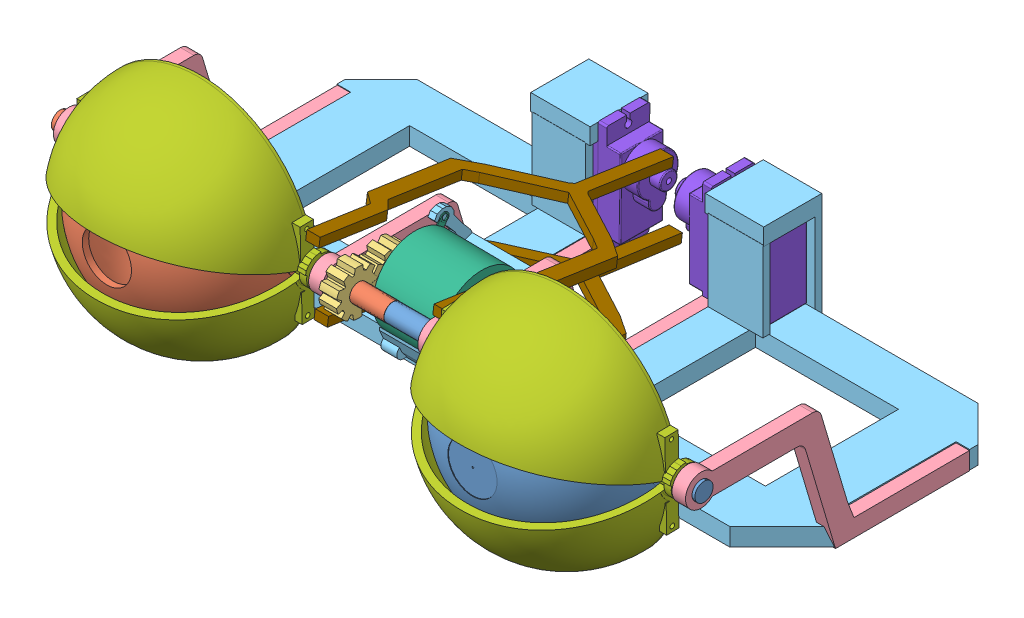
SolidWorks assembly EyeCam_Assem1, configuration Default. Lengths in mm.
Overall size (182.96 65.46 123.97).
16 component instances, 9 part files, 8 mates.
Components (placement in the parent):
- EyeBall_Lest-1: EyeBall_Lest [Default] at (6.3648 45.3908 60.6229) size (93.2 58.32 30.82)
- EyeBall_Right-1: EyeBall_Right [Default] at (-97.5461 45.3908 60.6229) x (1 0 0) z (0 0.002508 0.999997) size (94.55 58.32 30.82)
- Gear_motor-1: Gear_motor [Default] at (-58.0536 45.3908 60.6229) x (0 -0.838718 -0.544566) z (1 0 0) size (12.7 12.55 7.34)
- Eye_Connectors-1: Eye_Connectors [Default] at (44.3518 11.782 60.528) x (0 -0.002823 0.999996) z (-1 0 0) size (80.66 38.07 3.81)
- Eye_Connectors-2: Eye_Connectors [Default] at (-131.4997 11.7822 60.4795) x (0 -0.004267 0.999991) z (-1 0 0) size (80.66 38.07 3.81)
- Eye_Connectors-3: Eye_Connectors [Default] at (-27.9259 11.7821 60.4909) x (0 -0.003927 0.999992) z (-1 0 0) size (80.66 38.07 3.81)
- Eye_Connectors-4: Eye_Connectors [Default] at (-58.9604 11.7822 60.4852) x (0 -0.004097 0.999992) z (-1 0 0) size (80.66 38.07 3.81)
- Base-1: Base [Default] at (-45.5332 12.2077 4.6015) size (179.84 42.51 85.76)
- Motor1-1: Motor1 [Default] at (-52.4166 41.2525 45.1647) x (0.008727 0.814085 -0.580681) z (0.999962 -0.007104 0.005068) size (30.28 23.88 22.6)
- Eye_Lid-1: Eye_Lid [Default] at (6.3006 45.3908 60.6229) x (0 -0.018925 0.999821) z (-1 0 0) size (36.74 63.5 67.56)
- Eye_Lid-2: Eye_Lid [Default] at (-97.3353 45.3908 60.6229) x (0 -0.021534 0.999768) z (-1 0 0) size (36.74 63.5 67.56)
- Gear_motor-2: Gear_motor [Default] at (-58.0042 45.1272 50.5128) x (0.005068 0.000013 -0.999987) z (0.999962 -0.007104 0.005068) size (12.7 12.55 7.34)
- sg90-1: sg90 [Default] at (-14.0745 40.264 -27.9601) x (-0.008726 -0.999924 -0.008727) z (0.000076 0.008726 -0.999962) size (32.2 29.1 12.2)
- sg90-2: sg90 [Default] at (-76.3502 40.4687 -15.7594) x (-0.008727 -0.999962 0) z (0 0 1) size (32.2 29.1 12.2)
- Connector-1: Connector [Default] at (-43.8038 22.663 -19.9831) x (-0.999962 -0.001139 -0.008652) z (0.008727 -0.130521 -0.991407) size (47.89 2.79 82.55)
- Connector-2: Connector [Default] at (-44.3878 42.0646 -18.0603) x (-0.999962 -0.001214 -0.008642) z (0.008727 -0.139168 -0.99023) size (47.89 2.79 82.55)
Mates (geometry in assembly coordinates):
- Concentric1: concentric anti-aligned: cylinder of EyeBall_Lest-1 through (-21.5682 45.3908 60.6229) axis (-1 0 0) radius 2.5419; cylinder of EyeBall_Right-1 through (-69.3016 45.3908 60.6229) axis (1 0 0) radius 2.5953
- Concentric3: concentric anti-aligned: cylinder of EyeBall_Lest-1 through (34.2059 45.3908 60.6229) axis (1 0 0) radius 2.5953; cylinder of Eye_Connectors-1 through (45.6218 45.3908 60.6229) axis (-1 0 0) radius 2.4377
- Concentric4: concentric aligned: cylinder of EyeBall_Right-1 through (-125.3487 45.3908 60.6229) axis (-1 0 0) radius 2.5419; cylinder of Eye_Connectors-2 through (-130.2297 45.3908 60.6229) axis (-1 0 0) radius 2.4377
- Concentric5: concentric anti-aligned: cylinder of EyeBall_Right-1 through (-69.3016 45.3908 60.6229) axis (1 0 0) radius 2.5953; cylinder of Eye_Connectors-4 through (-57.6904 45.3908 60.6229) axis (-1 0 0) radius 2.4377
- Concentric6: concentric aligned: cylinder of EyeBall_Right-1 through (-69.3016 45.3908 60.6229) axis (1 0 0) radius 2.5953; circle of Eye_Connectors-3
- Concentric7: concentric anti-aligned: cylinder of EyeBall_Lest-1 through (34.2059 45.3908 60.6229) axis (1 0 0) radius 2.5953; cylinder of Eye_Lid-1 through (51.5126 45.3908 60.6229) axis (-1 0 0) radius 2.609
- Coincident1: coincident: point of Gear-1; plane of Eye_Connectors-4 through (-62.7704 48.5044 60.6357) normal (0 0.999992 0.004097)
- Concentric8: concentric anti-aligned: cylinder of EyeBall_Right-1 through (-69.3016 45.3908 60.6229) axis (1 0 0) radius 2.5953; cylinder of Eye_Lid-2 through (-52.1233 45.3908 60.6229) axis (-1 0 0) radius 2.609
